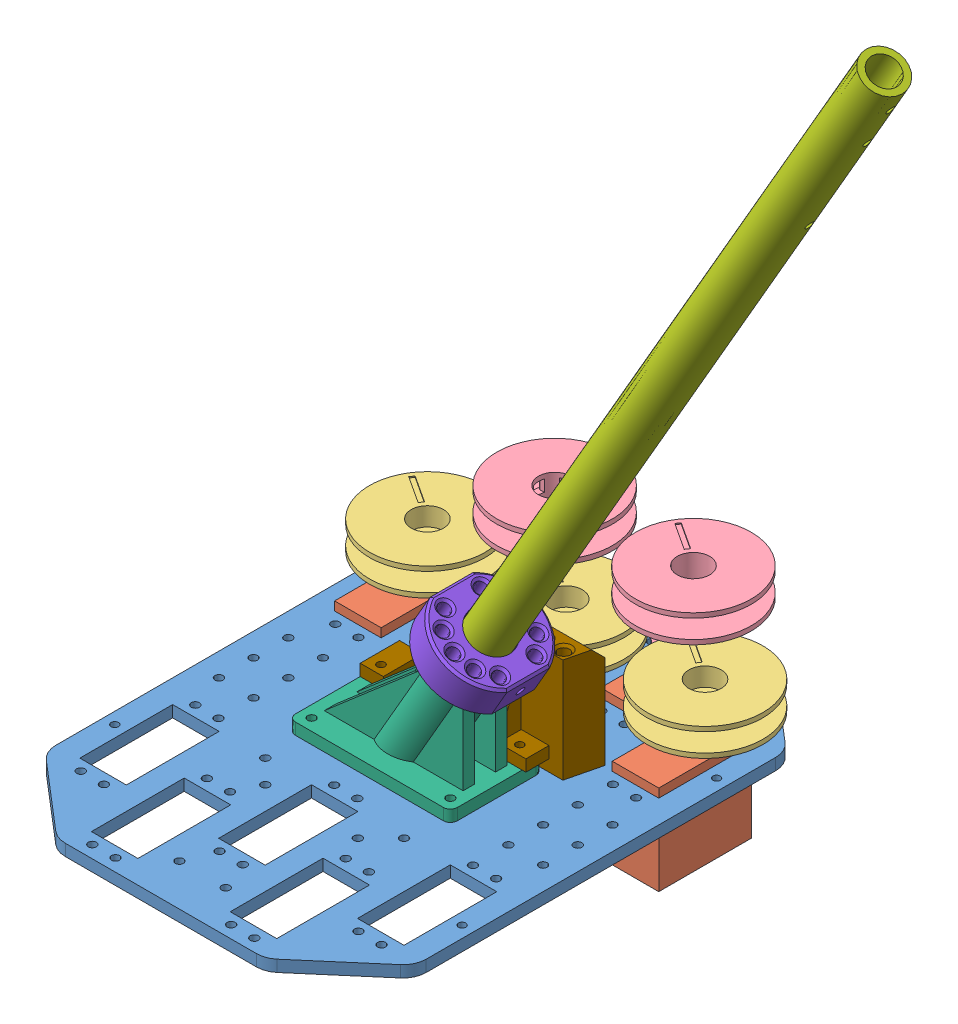
SolidWorks assembly assem_set_motor, configuration ﾃﾞﾌｫﾙﾄ. Lengths in mm.
Overall size (306.66 420.24 238.6).
22 component instances, 9 part files, 8 mates.
Components (placement in the parent):
- base_motor-1: base_motor [ﾃﾞﾌｫﾙﾄ] at origin size (190.97 114.3 238.6)
  - base-1: base [ﾃﾞﾌｫﾙﾄ] at origin size (160.1 5 220.2)
  - motor-1: motor [ﾃﾞﾌｫﾙﾄ] at (0 -30 -30.05) x (0 0 1) z (-1 0 0) size (73.36 59.5 70.97)
    - FB5311M-1: FB5311M [ﾃﾞﾌｫﾙﾄ] at origin size (54 44.25 20.1)
    - servo_horn_short-1: servo_horn_short [ﾃﾞﾌｫﾙﾄ] at (-10 42.5 0) x (-0.837169 0 -0.546944) z (0 1 0) size (50 57.04 17)
  - motor-2: motor [ﾃﾞﾌｫﾙﾄ] at (-60 -30 -30.05) x (0 0 1) z (-1 0 0) size (73.36 59.5 70.97)
    - FB5311M-1: FB5311M [ﾃﾞﾌｫﾙﾄ] at origin size (54 44.25 20.1)
    - servo_horn_short-1: servo_horn_short [ﾃﾞﾌｫﾙﾄ] at (-10 42.5 0) x (-0.837169 0 -0.546944) z (0 1 0) size (50 57.04 17)
  - motor-3: motor [ﾃﾞﾌｫﾙﾄ] at (60 -30 -30.05) x (0 0 1) z (-1 0 0) size (73.36 59.5 70.97)
    - FB5311M-1: FB5311M [ﾃﾞﾌｫﾙﾄ] at origin size (54 44.25 20.1)
    - servo_horn_short-1: servo_horn_short [ﾃﾞﾌｫﾙﾄ] at (-10 42.5 0) x (-0.837169 0 -0.546944) z (0 1 0) size (50 57.04 17)
  - motor_long-6: motor_long [ﾃﾞﾌｫﾙﾄ] at (-30 -30 -55.05) x (0 0 1) z (-1 0 0) size (75.45 74.5 73.44) (flexible)
    - FB5311M-1: FB5311M [ﾃﾞﾌｫﾙﾄ] at origin size (54 44.25 20.1)
    - servo_horn_long-1: servo_horn_long [ﾃﾞﾌｫﾙﾄ] at (-10 42.5 0) x (0.789041 0 0.61434) z (0 1 0) size (50 57.04 32)
  - motor_long-5: motor_long [ﾃﾞﾌｫﾙﾄ] at (30 -30 -55.05) x (0 0 1) z (-1 0 0) size (75.45 74.5 73.44)
    - FB5311M-1: FB5311M [ﾃﾞﾌｫﾙﾄ] at origin size (54 44.25 20.1)
    - servo_horn_long-1: servo_horn_long [ﾃﾞﾌｫﾙﾄ] at (-10 42.5 0) x (-0.837169 0 -0.546944) z (0 1 0) size (50 57.04 32)
  - wheel_support-1: wheel_support [ﾃﾞﾌｫﾙﾄ] at (0 0 -67.1) x (0 0 1) z (0 -1 0) size (28.5 32 55)
  - connector_45-1: connector_45 [ﾃﾞﾌｫﾙﾄ] at (0 10 25) x (0 0 1) z (0 1 0) size (40 70.39 54.3)
- pipe_body-1: pipe_body [body] at (202.5 360.7403 25) x (0.866025 -0.5 0) z (-0.5 -0.866025 0) size (18 18 400)
- wire_from_base_mini-1: wire_from_base_mini [ﾃﾞﾌｫﾙﾄ] at (25 53.3013 25) x (0 0 -1) z (0.5 0.866025 0) size (42.5 38.28 15)
- root_connector_loft-1: root_connector_loft [ﾃﾞﾌｫﾙﾄ] at (0 5 -10) x (0 0 -1) z (1 0 0) size (39 45 81.16)
Mates (geometry in assembly coordinates):
- 同心円1: concentric aligned: cylinder of base_motor-1/connector_45-1 through (-37.5993 54.802 25) axis (0.866025 -0.5 0) radius 1.75; cylinder of pipe_body-1 through (2.2058 31.8205 25) axis (0.866025 -0.5 0) radius 1.75
- 同心円2: concentric aligned: cylinder of base_motor-1/connector_45-1 through (-27.5993 72.1225 25) axis (0.866025 -0.5 0) radius 1.75; cylinder of pipe_body-1 through (12.2058 49.141 25) axis (0.866025 -0.5 0) radius 1.75
- 同心円3: concentric aligned: cylinder of base_motor-1/connector_45-1 through (-10.9151 -8.9054 25) axis (0.5 0.866025 0) radius 9.4; cylinder of pipe_body-1 through (2.5 14.3301 25) axis (0.5 0.866025 0) radius 9
- 同心円4: concentric anti-aligned: cylinder of pipe_body-1 through (2.5 14.3301 25) axis (0.5 0.866025 0) radius 9; cylinder of wire_from_base_mini-1 through (32.5 66.2917 25) axis (-0.5 -0.866025 0) radius 9.25
- 同心円5: concentric anti-aligned: cylinder of pipe_body-1 through (20.9558 64.2965 25) axis (0.866025 -0.5 0) radius 1.75; cylinder of wire_from_base_mini-1 through (16.5045 66.8664 25) axis (-0.866025 0.5 0) radius 3.5
- 同心円7: concentric anti-aligned: cylinder of base_motor-1/base-1 through (20 0 -20) axis (0 1 0) radius 1.75; cylinder of root_connector_loft-1 through (20 10 -20) axis (0 -1 0) radius 1.75
- 一致1: coincident anti-aligned: plane of base_motor-1/base-1 through (0 5 50) normal (0 1 0); plane of root_connector_loft-1 through (0 5 -10) normal (0 -1 0)
- 同心円8: concentric anti-aligned: cylinder of base_motor-1/base-1 through (-30 0 -10) axis (0 1 0) radius 1.75; cylinder of root_connector_loft-1 through (-30 10 -10) axis (0 -1 0) radius 1.75
